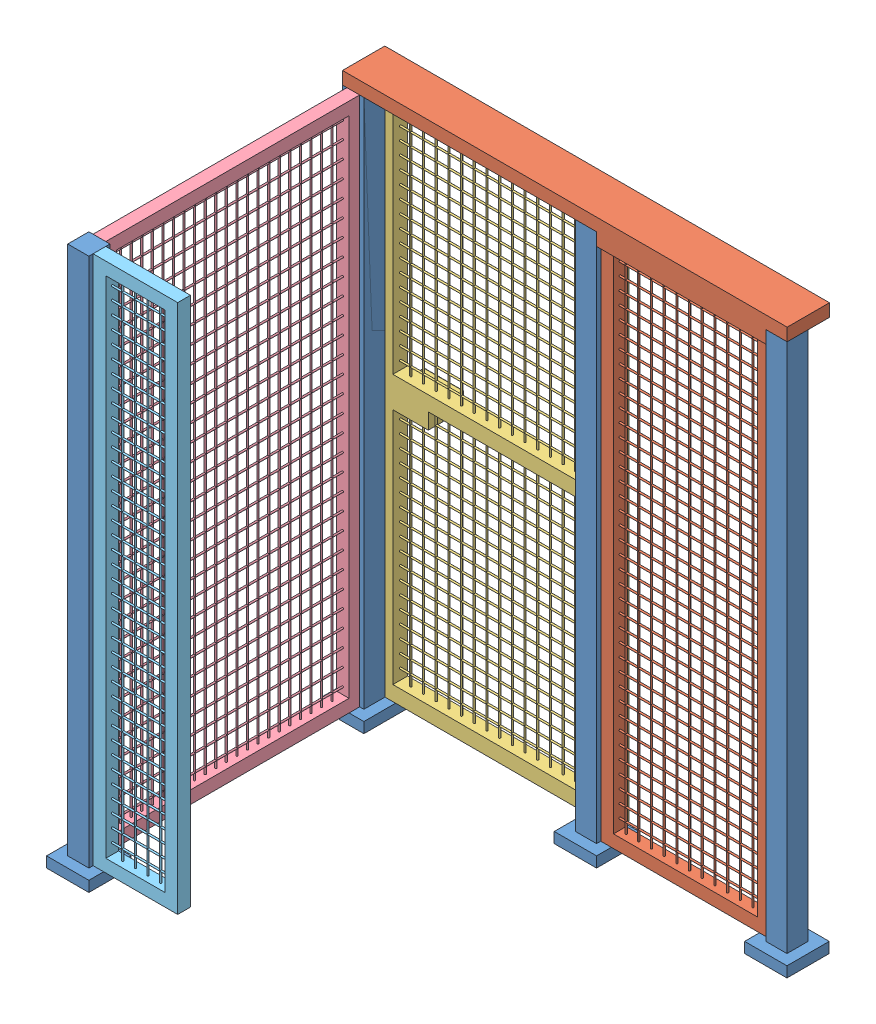
SolidWorks assembly Assieme1, configuration Default. Lengths in mm.
Overall size (2200 2615 1620).
9 component instances, 5 part files, 24 mates.
Components (placement in the parent):
- palo_barriera-2: palo_barriera [Default] at origin size (200 2555 200)
- palo_barriera-3: palo_barriera [Default] at (2000 0 0) size (200 2555 200)
- palo_barriera-4: palo_barriera [Default] at (1100 0 0) size (200 2555 200)
- Parte1^Assieme1-1: Parte1^Assieme1 [Default] at (1950 0 0) x (0 0 1) z (-1 0 0) size (200 2565 2102) (virtual)
- Parte2^Assieme1-1: Parte2^Assieme1 [Default] at (1950 2585 0) x (0 0 -1) z (0 -1 0) size (170 1090 2535) (virtual)
- palo_barriera-5: palo_barriera [Default] at (0 0 1300) size (200 2555 200)
- rete1m_c-1: rete1m_c [Default] at (0 0 -700) size (60 2505 1200)
- bariera_400mm-2: bariera_400mm [Default] at (450 0 1300) x (0 0 1) z (-1 0 0) size (60 2505 400)
- palo_barriera-6: palo_barriera [Default] at origin size (200 2555 200)
Mates (geometry in assembly coordinates):
- Coincidente26: coincident aligned: plane of palo_barriera-2 through (0 2555 0) normal (0 1 0); plane of palo_barriera-3 through (2000 2555 0) normal (0 1 0)
- Coincidente27: coincident aligned: plane of palo_barriera-2 through (-50 2550 50) normal (0 0 1); plane of palo_barriera-3 through (1950 2550 50) normal (0 0 1)
- Distanza10: distance = 1900 mm anti-aligned: plane of palo_barriera-3 through (1950 2550 -50) normal (-1 0 0); plane of palo_barriera-2 through (50 2550 -50) normal (1 0 0)
- Coincidente29: coincident aligned: plane of palo_barriera-3 through (2000 0 -100) normal (0 0 -1); plane of palo_barriera-4 through (1100 0 -100) normal (0 0 -1)
- Coincidente30: coincident aligned: plane of palo_barriera-3 through (2000 2555 0) normal (0 1 0); plane of palo_barriera-4 through (1100 2555 0) normal (0 1 0)
- Distanza11: distance = 800 mm anti-aligned: plane of palo_barriera-4 through (1150 2550 -50) normal (1 0 0); plane of palo_barriera-3 through (1950 2550 -50) normal (-1 0 0)
- SulPosto1: in place: plane of ? through (3950 2550 1950) normal (-1 0 0); plane of ? through (3950 0 0) normal (-1 0 0); moOrthogonalPlaneRef_w of ? through (3950 2550 1950) normal (-1 0 0); plane of ? through (3950 0 0) normal (0 1 0); plane of ? through (3950 2550 1950) normal (-1 0 0); plane of ? through (3950 0 0) normal (0 0 1); plane of palo_barriera-3 through (1950 2550 -50) normal (-1 0 0); unknown of Parte1^Assieme1-1
- Coincidente32: coincident aligned: plane of palo_barriera-3; plane of Parte1^Assieme1-1
- Coincidente33: coincident aligned: moOrthogonalPlaneRef_w of palo_barriera-3 through (1950 0 0) normal (0 1 0); plane of Parte1^Assieme1-1 through (1950 0 0) normal (0 1 0)
- Coincidente34: coincident anti-aligned: moOrthogonalPlaneRef_w of palo_barriera-3 through (1950 0 0) normal (0 0 -1); plane of Parte1^Assieme1-1 through (1950 0 0) normal (0 0 1)
- SulPosto2: in place: plane of ? through (1741.1939 2585 1880) normal (0 -1 0); plane of ? through (0 2585 0) normal (0 -1 0); plane of ? through (1741.1939 2585 1880) normal (0 -1 0); plane of ? through (0 2585 0) normal (0 0 -1); plane of ? through (1741.1939 2585 1880) normal (0 -1 0); plane of ? through (0 2585 0) normal (-1 0 0); plane of Parte1^Assieme1-1 through (-258.8061 2585 -120) normal (0 -1 0); unknown of Parte2^Assieme1-1
- Coincidente35: coincident aligned: plane of Parte1^Assieme1-1; plane of Parte2^Assieme1-1
- Coincidente36: coincident aligned: moOrthogonalPlaneRef_w of Parte1^Assieme1-1 through (1950 2585 0) normal (1 0 0); plane of Parte2^Assieme1-1 through (1950 2585 0) normal (1 0 0)
- Coincidente37: coincident anti-aligned: moOrthogonalPlaneRef_w of Parte1^Assieme1-1 through (1950 2585 0) normal (0 0 1); plane of Parte2^Assieme1-1 through (1950 2585 0) normal (0 0 -1)
- Distanza16: distance = 1200 mm anti-aligned: plane of palo_barriera-5 through (-50 2550 1250) normal (0 0 -1); plane of palo_barriera-2 through (-50 2550 50) normal (0 0 1)
- Coincidente56: coincident aligned: plane of palo_barriera-2 through (-50 2550 -50) normal (-1 0 0); plane of palo_barriera-5 through (-50 2550 1250) normal (-1 0 0)
- Coincidente57: coincident aligned: plane of palo_barriera-2 through (0 0 100) normal (0 -1 0); plane of palo_barriera-5 through (0 0 1400) normal (0 -1 0)
- Coincidente64: coincident anti-aligned: plane of palo_barriera-2 through (-50 2550 50) normal (0 0 1); plane of rete1m_c-1 through (0 0 50) normal (0 0 -1)
- Distanza22: distance = 20 mm aligned: plane of rete1m_c-1 through (-30 110 50) normal (-1 0 0); plane of palo_barriera-2 through (-50 2550 -50) normal (-1 0 0)
- Coincidente66: coincident aligned: plane of palo_barriera-5 through (0 2555 1300) normal (0 1 0); plane of rete1m_c-1 through (30 2555 50) normal (0 1 0)
- Coincidente67: coordinate: point of palo_barriera-2
- Coincidente68: coincident anti-aligned: plane of palo_barriera-5 through (50 2550 1250) normal (1 0 0); plane of bariera_400mm-2 through (50 0 1300) normal (-1 0 0)
- Coincidente69: coincident aligned: plane of palo_barriera-5 through (0 2555 1300) normal (0 1 0); plane of bariera_400mm-2 through (450 2555 1300) normal (0 1 0)
- Distanza23: distance = 20 mm aligned: plane of bariera_400mm-2 through (50 50 1330) normal (0 0 1); plane of palo_barriera-5 through (-50 2550 1350) normal (0 0 1)
